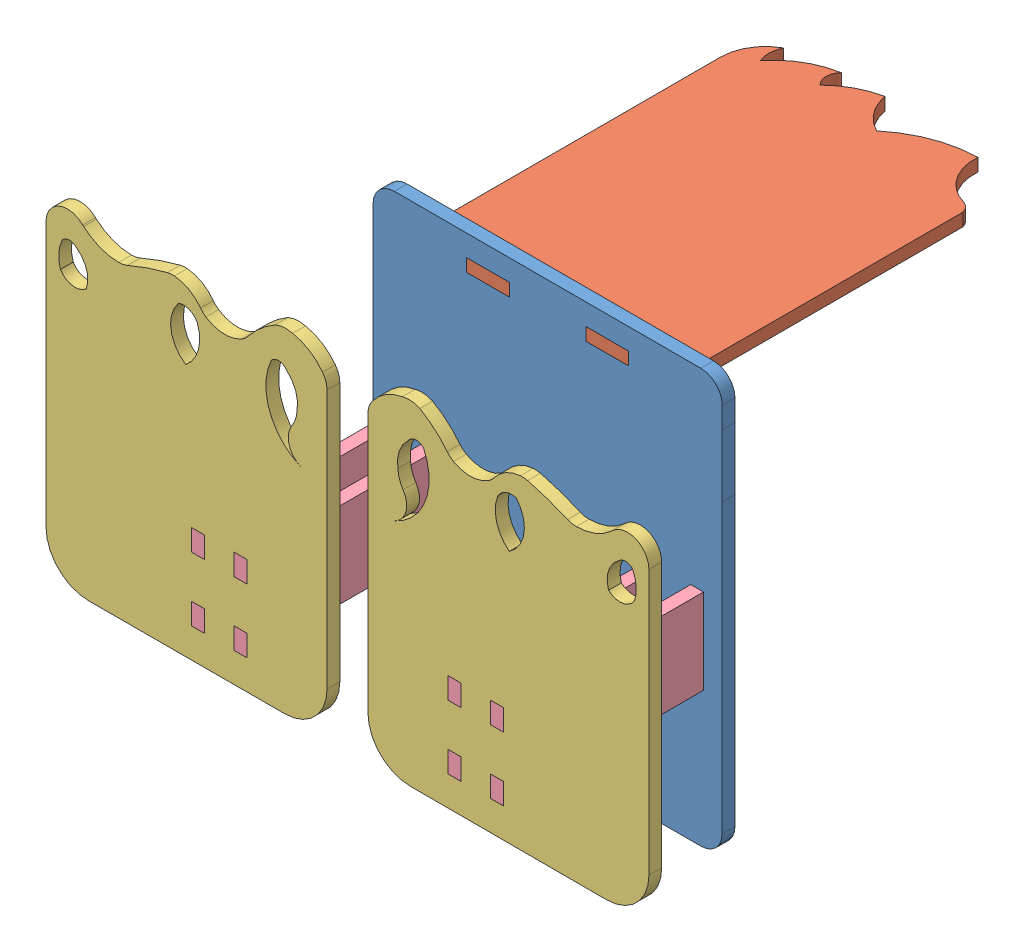
SolidWorks assembly Ensamblaje1, configuration Predeterminado. Lengths in mm.
Overall size (141.6 103.58 128.91).
8 component instances, 4 part files, 21 mates.
Components (placement in the parent):
- base-1: base [Predeterminado] at (-187.8528 -20.7333 95.6838) size (82 97.18 3)
- face-1: face [Predeterminado] at (-154.0884 61.7844 1.898) x (0 0 1) z (0 1 0) size (81.91 60 3)
- foot-1: foot [Predeterminado] at (-116.0465 34.9988 145.6838) x (-1 0 0) z (0 0 -1) size (66 78.56 3)
- leg-1: leg [Predeterminado] at (-170.6695 1.0357 99.4222) x (0 0 1) z (-1 0 0) size (50 20 3)
- leg-2: leg [Predeterminado] at (-113.4726 28.1654 99.4222) x (0 0 1) z (1 0 0) size (50 20 3)
- leg-3: leg [Predeterminado] at (-100.4726 28.1654 141.9454) x (0 0 -1) z (-1 0 0) size (50 20 3)
- leg-4: leg [Predeterminado] at (-160.6695 1.0357 99.4222) x (0 0 1) z (-1 0 0) size (50 20 3)
- foot-2: foot [Predeterminado] at (-158.0956 34.9988 142.6838) size (66 78.56 3)
Mates (geometry in assembly coordinates):
- Coincidente2: coincident aligned: plane of foot-1 through (-116.0465 34.9988 145.6838) normal (0 0 1); plane of leg-1 through (-173.6695 19.6006 145.6838) normal (0 0 1)
- Coincidente4: coincident anti-aligned: plane of foot-1 through (-116.0465 24.6006 142.6838) normal (0 -1 0); plane of leg-1 through (-173.6695 24.6006 145.6838) normal (0 1 0)
- Coincidente5: coincident anti-aligned: plane of foot-1 through (-173.6695 34.9988 142.6838) normal (1 0 0); plane of leg-1 through (-173.6695 1.0357 99.4222) normal (-1 0 0)
- Coincidente6: coincident anti-aligned: plane of foot-1 through (-163.6695 34.9988 142.6838) normal (1 0 0); plane of leg-4 through (-163.6695 1.0357 99.4222) normal (-1 0 0)
- Coincidente7: coincident anti-aligned: plane of foot-1 through (-116.0465 4.6006 142.6838) normal (0 1 0); plane of leg-4 through (-163.6695 4.6006 145.6838) normal (0 -1 0)
- Coincidente8: coincident aligned: plane of foot-1 through (-116.0465 34.9988 145.6838) normal (0 0 1); plane of leg-4 through (-163.6695 9.6006 145.6838) normal (0 0 1)
- Coincidente9: coincident anti-aligned: plane of leg-3 through (-100.4726 28.1654 141.9454) normal (1 0 0); plane of foot-2 through (-100.4726 34.9988 145.6838) normal (-1 0 0)
- Coincidente10: coincident anti-aligned: plane of leg-3 through (-103.4726 4.6006 95.6838) normal (0 -1 0); plane of foot-2 through (-158.0956 4.6006 145.6838) normal (0 1 0)
- Coincidente11: coincident aligned: plane of leg-3 through (-103.4726 19.6006 145.6838) normal (0 0 1); plane of foot-2 through (-158.0956 34.9988 145.6838) normal (0 0 1)
- Coincidente12: coincident anti-aligned: plane of leg-2 through (-113.4726 28.1654 99.4222) normal (-1 0 0); plane of foot-2 through (-113.4726 34.9988 145.6838) normal (1 0 0)
- Coincidente13: coincident anti-aligned: plane of leg-2 through (-110.4726 4.6006 145.6838) normal (0 -1 0); plane of foot-2 through (-158.0956 4.6006 145.6838) normal (0 1 0)
- Coincidente14: coincident aligned: plane of leg-2 through (-110.4726 9.6006 145.6838) normal (0 0 1); plane of foot-2 through (-158.0956 34.9988 145.6838) normal (0 0 1)
- Coincidente16: coincident anti-aligned: plane of base-1 through (-187.8528 4.6006 98.6838) normal (0 1 0); plane of leg-2 through (-110.4726 4.6006 145.6838) normal (0 -1 0)
- Coincidente17: coincident anti-aligned: plane of base-1 through (-113.4726 -20.7333 98.6838) normal (1 0 0); plane of leg-2 through (-113.4726 28.1654 99.4222) normal (-1 0 0)
- Coincidente18: coincident aligned: plane of base-1 through (-187.8528 -20.7333 95.6838) normal (0 0 -1); plane of leg-3 through (-103.4726 19.6006 95.6838) normal (0 0 -1)
- Coincidente19: coincident anti-aligned: plane of base-1 through (-160.6695 -20.7333 98.6838) normal (-1 0 0); plane of leg-4 through (-160.6695 1.0357 99.4222) normal (1 0 0)
- Coincidente20: coincident anti-aligned: plane of base-1 through (-187.8528 4.6006 98.6838) normal (0 1 0); plane of leg-1 through (-173.6695 4.6006 145.6838) normal (0 -1 0)
- Coincidente21: coincident aligned: plane of base-1 through (-187.8528 -20.7333 95.6838) normal (0 0 -1); plane of leg-1 through (-173.6695 19.6006 95.6838) normal (0 0 -1)
- Coincidente23: coincident: plane of base-1 through (-187.8528 64.7844 98.6838) normal (0 -1 0); plane of face-1 through (-112.4952 64.7844 31.8587) normal (0 1 0)
- Coincidente25: coincident: plane of base-1 through (-187.8528 -20.7333 98.6838) normal (0 0 1); plane of face-1 through (-130.578 64.7844 98.6838) normal (0 0 1)
- Coincidente26: coincident anti-aligned: plane of base-1 through (-118.0726 -20.7333 98.6838) normal (-1 0 0); plane of face-1 through (-118.0726 64.7844 98.6838) normal (1 0 0)
